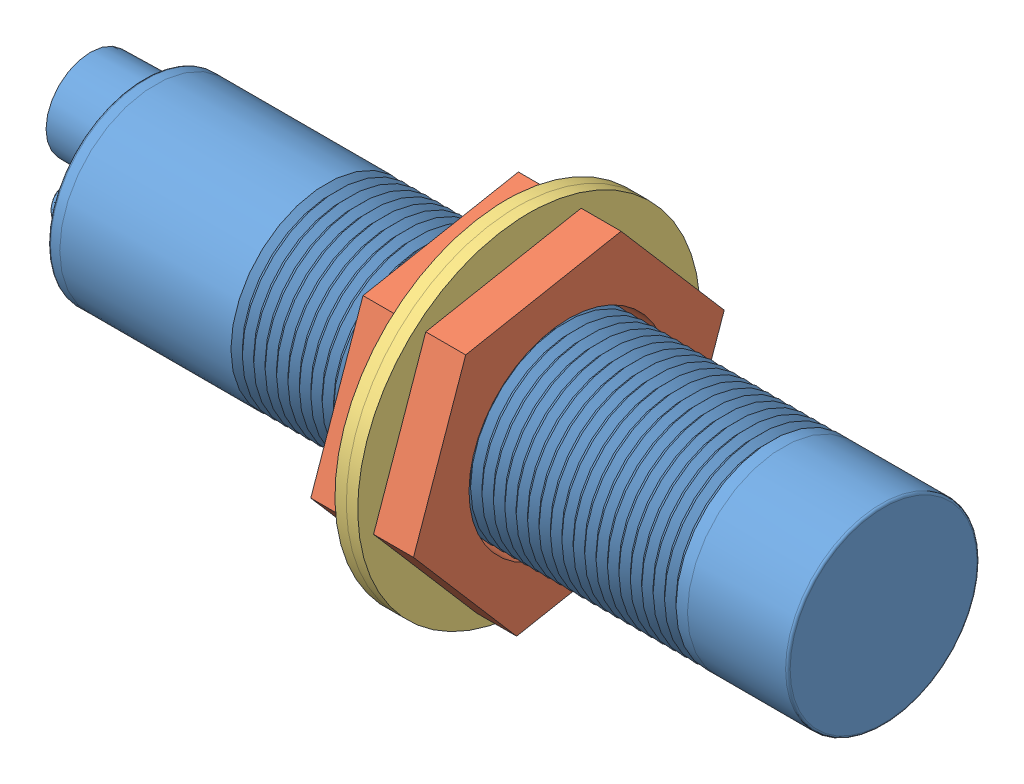
SolidWorks assembly Inductive Proximity Sensor, configuration Default. Lengths in mm.
Overall size (73.6 36.66 36.27).
5 component instances, 3 part files, 9 mates.
Components (placement in the parent):
- Sensor Body-1: Sensor Body [Default] at (-6.2225 39.7633 58.5792) size (73.6 17.21 17.21)
- Nut-1: Nut [Default] at (25.4974 39.7633 58.5792) x (0 0.757948 0.652315) z (0 -0.652315 0.757948) size (27.71 3.5 24)
- Nut-2: Nut [Default] at (30.9974 39.7633 58.5792) x (0 0.757948 0.652315) z (0 -0.652315 0.757948) size (27.71 3.5 24)
- Washer-1: Washer [Default] at (26.4974 39.7633 58.5792) x (0 0 -1) z (0 1 0) size (30 1 30)
- Washer-2: Washer [Default] at (27.4974 39.7633 58.5792) x (0 0 -1) z (0 1 0) size (30 1 30)
Mates (geometry in assembly coordinates):
- Concentric1: concentric anti-aligned: cylinder of Sensor Body-1 through (58.5775 39.7633 58.5792) axis (-1 0 0) radius 8.39; cylinder of Nut-1 through (21.9974 39.7633 58.5792) axis (1 0 0) radius 8.75
- Concentric2: concentric anti-aligned: cylinder of Sensor Body-1 through (49.7775 39.7633 58.5792) axis (-1 0 0) radius 8.395; cylinder of Washer-2 through (26.4974 39.7633 58.5792) axis (1 0 0) radius 15
- Concentric3: concentric anti-aligned: cylinder of Sensor Body-1 through (49.7775 39.7633 58.5792) axis (-1 0 0) radius 8.395; cylinder of Washer-1 through (25.4974 39.7633 58.5792) axis (1 0 0) radius 15
- Concentric4: concentric anti-aligned: cylinder of Sensor Body-1 through (49.7775 39.7633 58.5792) axis (-1 0 0) radius 8.395; cylinder of Nut-2 through (27.4974 39.7633 58.5792) axis (1 0 0) radius 8.75
- Coincident1: coincident anti-aligned: plane of Nut-2 through (27.4974 39.7633 58.5792) normal (-1 0 0); plane of Washer-2 through (27.4974 39.7633 58.5792) normal (1 0 0)
- Coincident2: coincident anti-aligned: plane of Washer-1 through (26.4974 39.7633 58.5792) normal (1 0 0); plane of Washer-2 through (26.4974 39.7633 58.5792) normal (-1 0 0)
- Coincident3: coincident anti-aligned: plane of Nut-1 through (25.4974 39.7633 58.5792) normal (1 0 0); plane of Washer-1 through (25.4974 39.7633 58.5792) normal (-1 0 0)
- Coincident4: coincident aligned: plane of Nut-1 through (21.9974 26.6843 63.1552) normal (0 -0.652315 0.757948); plane of Nut-2 through (27.4974 26.6843 63.1552) normal (0 -0.652315 0.757948)
- Screw1: screw = 1 anti-aligned: cylinder of Sensor Body-1 through (58.5775 39.7633 58.5792) axis (-1 0 0) radius 8.39; cylinder of Nut-2 through (27.4974 39.7633 58.5792) axis (1 0 0) radius 8.75
